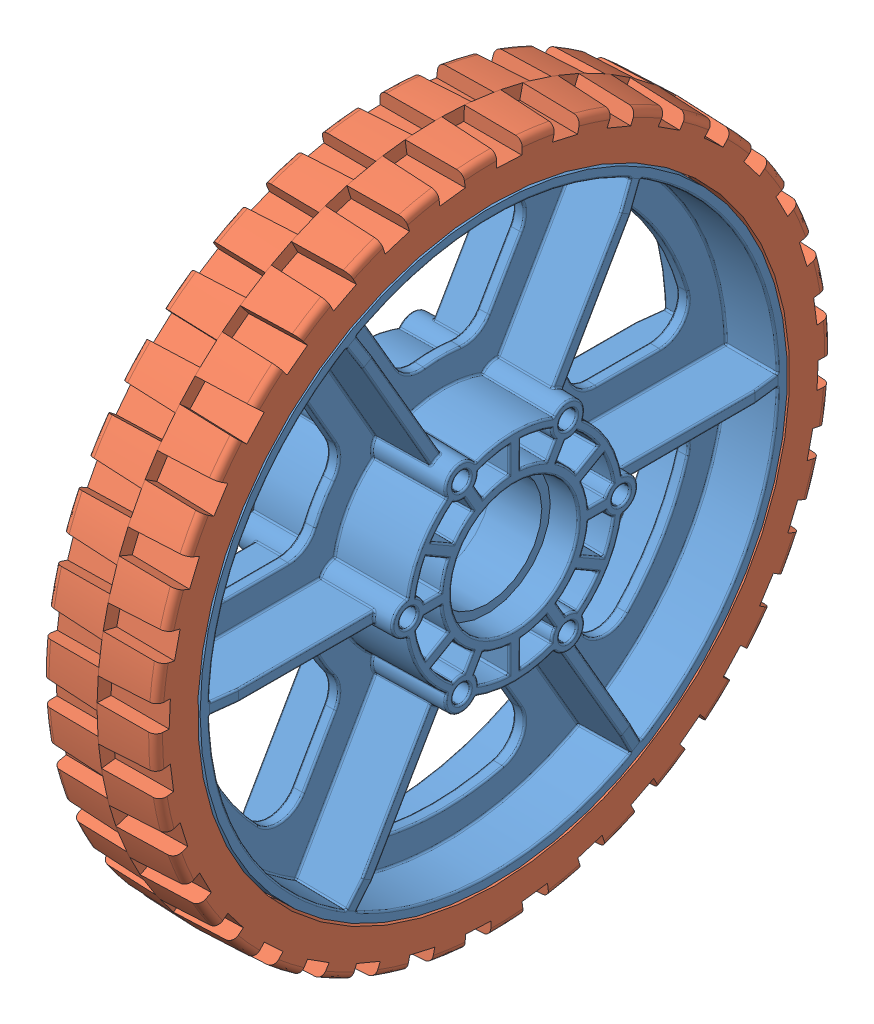
SolidWorks assembly Wheel_6inHiGrip, configuration Default. Lengths in mm.
Overall size (34.93 191.55 191.55).
2 component instances, 2 part files, 0 mates.
Components (placement in the parent):
- Wheel_6inHiGrip_Wheel-1: Wheel_6inHiGrip_Wheel [Default] at (-52.6446 9.4231 21.378) size (34.93 132.08 132.08)
- Wheel_6inHiGrip_Tread-1: Wheel_6inHiGrip_Tread [Default] at (-65.3446 9.4231 21.378) x (0 -0.304368 -0.952555) z (1 0 0) size (152.4 152.4 25.58)
